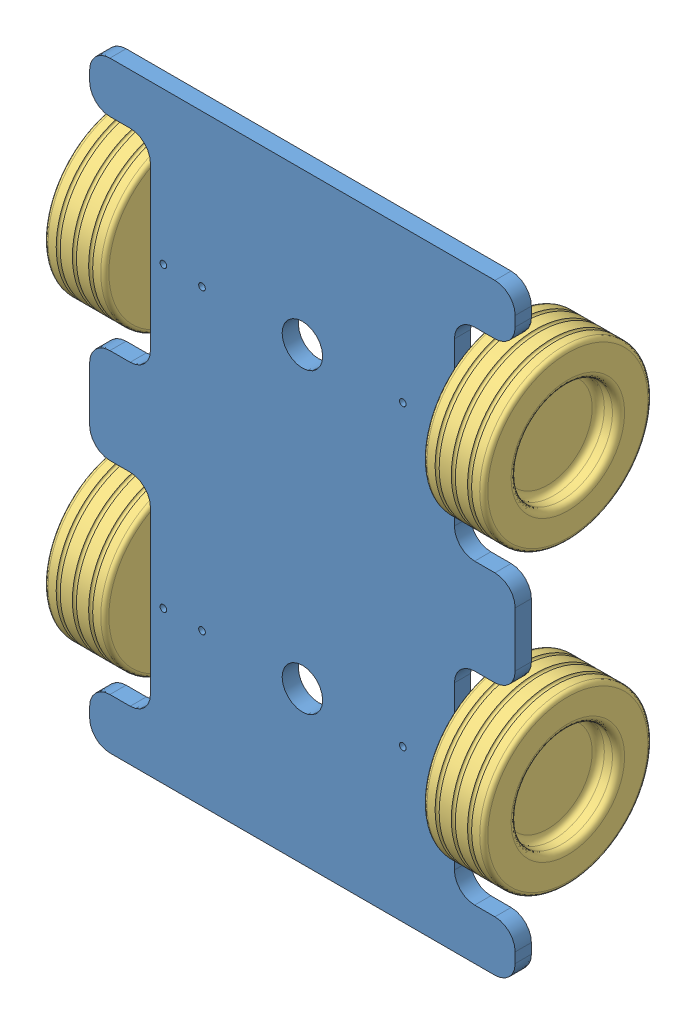
SolidWorks assembly Sestava2, configuration Výchozí. Lengths in mm.
Overall size (217 297 83).
13 component instances, 4 part files, 32 mates.
Components (placement in the parent):
- deskaX-1: deskaX [Výchozí] at (-115.2603 -148.2948 293) size (210 297 8)
- motor_plech-1: motor_plech [Výchozí] at (64.7397 -60.7948 293) x (-1 0 0) z (0 -1 0) size (52 27 25)
- motor_plech-2: motor_plech [Výchozí] at (64.7397 86.2052 293) x (-1 0 0) z (0 -1 0) size (52 27 25)
- motor_plech-3: motor_plech [Výchozí] at (-85.2603 -85.7948 293) x (1 0 0) z (0 1 0) size (52 27 25)
- motor_plech-4: motor_plech [Výchozí] at (-85.2603 61.2052 293) x (1 0 0) z (0 1 0) size (52 27 25)
- kolo-1: kolo [Výchozí] at (98.2397 -73.2948 278.5) x (0 0 1) z (-1 0 0) size (83 83 30)
- motor-1: motor [Výchozí] at (14.7397 -73.2948 278.5) x (0 -1 0) z (1 0 0) size (25 25 64.5)
- kolo-2: kolo [Výchozí] at (98.2397 73.7052 278.5) x (0 0 1) z (-1 0 0) size (83 83 30)
- motor-2: motor [Výchozí] at (14.7397 73.7052 278.5) x (0 1 0) z (1 0 0) size (25 25 64.5)
- kolo-3: kolo [Výchozí] at (-118.7603 73.7052 278.5) x (0 0 -1) z (1 0 0) size (83 83 30)
- motor-3: motor [Výchozí] at (-35.2603 73.7052 278.5) x (0 -1 0) z (-1 0 0) size (25 25 64.5)
- kolo-4: kolo [Výchozí] at (-118.7603 -73.2948 278.5) x (0 0 -1) z (1 0 0) size (83 83 30)
- motor-4: motor [Výchozí] at (-35.2603 -73.2948 278.5) x (0 -1 0) z (-1 0 0) size (25 25 64.5)
Mates (geometry in assembly coordinates):
- Soustředná1: concentric anti-aligned: cylinder of deskaX-1 through (58.3397 -73.2948 301) axis (0 0 -1) radius 1.65; cylinder of motor_plech-1 through (58.3397 -73.2948 283) axis (0 0 1) radius 1.65
- Soustředná2: concentric anti-aligned: cylinder of deskaX-1 through (39.2897 -73.2948 301) axis (0 0 -1) radius 1.65; cylinder of motor_plech-1 through (39.2897 -73.2948 283) axis (0 0 1) radius 1.65
- Sjednocená1: coincident anti-aligned: plane of deskaX-1 through (-115.2603 -148.2948 293) normal (0 0 -1); plane of motor_plech-1 through (12.7397 -85.7948 293) normal (0 0 1)
- Soustředná3: concentric anti-aligned: cylinder of deskaX-1 through (58.3397 73.7052 301) axis (0 0 -1) radius 1.65; cylinder of motor_plech-2 through (58.3397 73.7052 283) axis (0 0 1) radius 1.65
- Soustředná4: concentric anti-aligned: cylinder of deskaX-1 through (39.2897 73.7052 301) axis (0 0 -1) radius 1.65; cylinder of motor_plech-2 through (39.2897 73.7052 283) axis (0 0 1) radius 1.65
- Sjednocená2: coincident anti-aligned: plane of deskaX-1 through (-115.2603 -148.2948 293) normal (0 0 -1); plane of motor_plech-2 through (12.7397 61.2052 293) normal (0 0 1)
- Soustředná5: concentric anti-aligned: cylinder of deskaX-1 through (-78.8603 -73.2948 301) axis (0 0 -1) radius 1.65; cylinder of motor_plech-3 through (-78.8603 -73.2948 283) axis (0 0 1) radius 1.65
- Soustředná6: concentric anti-aligned: cylinder of deskaX-1 through (-59.8103 -73.2948 301) axis (0 0 -1) radius 1.65; cylinder of motor_plech-3 through (-59.8103 -73.2948 283) axis (0 0 1) radius 1.65
- Sjednocená3: coincident anti-aligned: plane of deskaX-1 through (-115.2603 -148.2948 293) normal (0 0 -1); plane of motor_plech-3 through (-33.2603 -60.7948 293) normal (0 0 1)
- Soustředná7: concentric anti-aligned: cylinder of deskaX-1 through (-78.8603 73.7052 301) axis (0 0 -1) radius 1.65; cylinder of motor_plech-4 through (-78.8603 73.7052 283) axis (0 0 1) radius 1.65
- Soustředná8: concentric anti-aligned: cylinder of deskaX-1 through (-59.8103 73.7052 301) axis (0 0 -1) radius 1.65; cylinder of motor_plech-4 through (-59.8103 73.7052 283) axis (0 0 1) radius 1.65
- Sjednocená4: coincident anti-aligned: plane of deskaX-1 through (-115.2603 -148.2948 293) normal (0 0 -1); plane of motor_plech-4 through (-33.2603 86.2052 293) normal (0 0 1)
- Soustředná9: concentric anti-aligned: cylinder of motor_plech-1 through (39.7397 -73.2948 278.5) axis (1 0 0) radius 3.75; cylinder of motor-1 through (65.2397 -73.2948 278.5) axis (-1 0 0) radius 3.5
- Soustředná10: concentric aligned: cylinder of motor_plech-1 through (39.7397 -73.2948 287) axis (1 0 0) radius 1.65; cylinder of motor-1 through (58.7397 -73.2948 287) axis (1 0 0) radius 1.65
- Sjednocená5: coincident anti-aligned: plane of motor_plech-1 through (62.7397 -85.7948 266) normal (-1 0 0); plane of motor-1 through (62.7397 -73.2948 278.5) normal (1 0 0)
- Soustředná11: concentric anti-aligned: cylinder of motor_plech-2 through (39.7397 73.7052 278.5) axis (1 0 0) radius 3.75; cylinder of motor-2 through (65.2397 73.7052 278.5) axis (-1 0 0) radius 3.5
- Soustředná12: concentric aligned: cylinder of motor_plech-2 through (39.7397 73.7052 287) axis (1 0 0) radius 1.65; cylinder of motor-2 through (58.7397 73.7052 287) axis (1 0 0) radius 1.65
- Sjednocená6: coincident anti-aligned: plane of motor_plech-2 through (62.7397 61.2052 266) normal (-1 0 0); plane of motor-2 through (62.7397 73.7052 278.5) normal (1 0 0)
- Soustředná13: concentric anti-aligned: cylinder of motor_plech-3 through (-60.2603 -73.2948 278.5) axis (-1 0 0) radius 3.75; cylinder of motor-4 through (-85.7603 -73.2948 278.5) axis (1 0 0) radius 3.5
- Soustředná14: concentric aligned: cylinder of motor_plech-3 through (-60.2603 -73.2948 287) axis (-1 0 0) radius 1.65; cylinder of motor-4 through (-79.2603 -73.2948 287) axis (-1 0 0) radius 1.65
- Sjednocená7: coincident anti-aligned: plane of motor_plech-3 through (-83.2603 -60.7948 266) normal (1 0 0); plane of motor-4 through (-83.2603 -73.2948 278.5) normal (-1 0 0)
- Soustředná15: concentric anti-aligned: cylinder of motor_plech-4 through (-60.2603 73.7052 278.5) axis (-1 0 0) radius 3.75; cylinder of motor-3 through (-85.7603 73.7052 278.5) axis (1 0 0) radius 3.5
- Soustředná16: concentric aligned: cylinder of motor_plech-4 through (-60.2603 73.7052 287) axis (-1 0 0) radius 1.65; cylinder of motor-3 through (-79.2603 73.7052 287) axis (-1 0 0) radius 1.65
- Sjednocená8: coincident anti-aligned: plane of motor_plech-4 through (-83.2603 86.2052 266) normal (1 0 0); plane of motor-3 through (-83.2603 73.7052 278.5) normal (-1 0 0)
- Soustředná17: concentric aligned: cylinder of kolo-3 through (-95.7603 73.7052 278.5) axis (1 0 0) radius 1.65; cylinder of motor-3 through (-95.7603 73.7052 278.5) axis (1 0 0) radius 2
- Soustředná18: concentric aligned: cylinder of kolo-4 through (-95.7603 -73.2948 278.5) axis (1 0 0) radius 1.65; cylinder of motor-4 through (-95.7603 -73.2948 278.5) axis (1 0 0) radius 2
- Soustředná19: concentric aligned: cylinder of kolo-1 through (75.2397 -73.2948 278.5) axis (-1 0 0) radius 1.65; cylinder of motor-1 through (75.2397 -73.2948 278.5) axis (-1 0 0) radius 2
- Soustředná20: concentric aligned: cylinder of kolo-2 through (75.2397 73.7052 278.5) axis (-1 0 0) radius 1.65; cylinder of motor-2 through (75.2397 73.7052 278.5) axis (-1 0 0) radius 2
- Sjednocená9: coincident anti-aligned: plane of kolo-1 through (75.2397 -73.2948 278.5) normal (-1 0 0); plane of motor-1 through (75.2397 -73.2948 278.5) normal (1 0 0)
- Sjednocená10: coincident anti-aligned: plane of kolo-2 through (75.2397 73.7052 278.5) normal (-1 0 0); plane of motor-2 through (75.2397 73.7052 278.5) normal (1 0 0)
- Sjednocená11: coincident anti-aligned: plane of kolo-3 through (-95.7603 73.7052 278.5) normal (1 0 0); plane of motor-3 through (-95.7603 73.7052 278.5) normal (-1 0 0)
- Sjednocená12: coincident anti-aligned: plane of kolo-4 through (-95.7603 -73.2948 278.5) normal (1 0 0); plane of motor-4 through (-95.7603 -73.2948 278.5) normal (-1 0 0)
